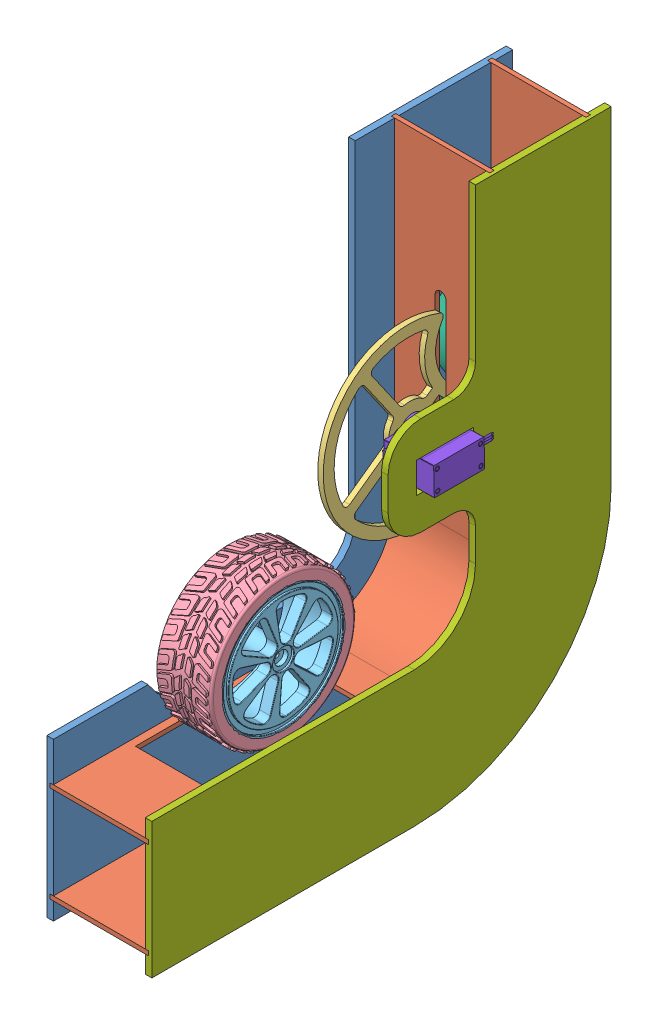
SolidWorks assembly shooter-tunnel, configuration Default. Lengths in mm.
Overall size (62.86 265 210).
9 component instances, 8 part files, 13 mates.
Components (placement in the parent):
- shooter-tunnel-inside-1: shooter-tunnel-inside [Default] at (-24.3201 3.4621 -25.6918) size (3 265 210)
- shooter-tunnel-sides-1: shooter-tunnel-sides [Default] at (-22.8201 3.4621 -25.6918) size (45 232 202)
- geneva-wheel-1: geneva-wheel [Default] at (-1.7331 49.625 -46.9668) x (0.999681 0.025253 0) z (-0.014331 0.567311 -0.823379) size (2.5 80 73.44)
- Wheel Assemble-1: Wheel Assemble [Default] at (-10.1485 0.69 25.1891) x (0 -0.924225 -0.381849) z (1 0 0) size (68 68 25)
  - Tire-1-1: Tire-1 [Default] at origin size (68 68 24.89)
  - WheelFrame-2-1: WheelFrame-2 [Default] at (-797.8323 -276.5666 -0.108) size (56.38 56.38 25)
- TT-Ball-1: TT-Ball [Default] at (-0.3201 68.2624 -84.8234) x (-0.633894 -0.040497 0.772359) z (-0.187075 0.977003 -0.10231) size (40 40 40)
- shooter-tunnel-outside-1: shooter-tunnel-outside [Default] at (17.6799 3.4621 -25.6918) size (3 265 210)
- micro-servo-2: micro-servo [Default] at (12.3724 49.9813 -45.5618) x (0 0 1) z (0.025253 -0.999681 0) size (36.67 29.95 12.59)
Mates (geometry in assembly coordinates):
- Coincident1: coincident anti-aligned: plane of shooter-tunnel-inside-1 through (-22.8201 3.4621 -105.6918) normal (0 0 -1); plane of shooter-tunnel-sides-1 through (22.1799 3.4621 -105.6918) normal (0 0 1)
- Coincident2: coincident aligned: plane of shooter-tunnel-inside-1 through (-21.3201 153.4621 -43.6918) normal (0 1 0); plane of shooter-tunnel-sides-1 through (22.1799 153.4621 -25.6918) normal (0 1 0)
- Coincident3: coincident anti-aligned: plane of shooter-tunnel-inside-1 through (-22.8201 3.4621 -25.6918) normal (1 0 0); plane of shooter-tunnel-sides-1 through (-22.8201 3.4621 -25.6918) normal (-1 0 0)
- Parallel1: parallel aligned: plane of shooter-tunnel-inside-1 through (-24.3201 3.4621 -25.6918) normal (-1 0 0); plane of Wheel Assemble-1/WheelFrame-2-1 through (-10.2565 0.69 25.1891) normal (-1 0 0)
- Parallel2: parallel aligned: plane of shooter-tunnel-inside-1 through (-24.3201 3.4621 -25.6918) normal (-1 0 0); plane of Wheel Assemble-1/WheelFrame-2-1 through (-10.2565 0.69 25.1891) normal (-1 0 0)
- Distance2: distance = 1 mm anti-aligned: sphere of TT-Ball-1; plane of shooter-tunnel-inside-1 through (-21.3201 3.4621 -25.6918) normal (1 0 0)
- Coincident8: coincident anti-aligned: plane of shooter-tunnel-sides-1 through (22.1799 -76.5379 -25.6918) normal (0 1 0); plane of shooter-tunnel-outside-1 through (22.1799 -76.5379 -25.6918) normal (0 -1 0)
- Coincident9: coincident aligned: plane of shooter-tunnel-sides-1 through (22.1799 3.4621 94.3082) normal (0 0 1); plane of shooter-tunnel-outside-1 through (20.6799 -24.5379 94.3082) normal (0 0 1)
- Coincident11: coincident anti-aligned: plane of shooter-tunnel-sides-1 through (22.1799 3.4621 -25.6918) normal (1 0 0); plane of shooter-tunnel-outside-1 through (22.1799 3.4621 -25.6918) normal (-1 0 0)
- Coincident16: coincident anti-aligned: plane of shooter-tunnel-outside-1 through (20.6799 43.9621 -52.6918) normal (0 0 1); plane of micro-servo-2 through (12.5314 43.6883 -52.6918) normal (0 0 -1)
- Concentric1: concentric aligned: cylinder of geneva-wheel-1 through (0.7661 49.6881 -46.9668) axis (-0.999681 -0.025253 0) radius 3.4; cylinder of micro-servo-2 through (2.7155 49.7374 -46.9668) axis (-0.999681 -0.025253 0) radius 2.3
- Distance3: distance = 2 mm anti-aligned: plane of micro-servo-2 through (-1.2332 49.6376 -46.9668) normal (-0.999681 -0.025253 0); plane of geneva-wheel-1 through (0.7661 49.6881 -46.9668) normal (0.999681 0.025253 0)
- Coincident17: coincident anti-aligned: plane of micro-servo-2 through (6.1425 43.9621 -25.0218) normal (0 -1 0); plane of shooter-tunnel-outside-1 through (20.6799 43.9621 -26.6918) normal (0 1 0)
